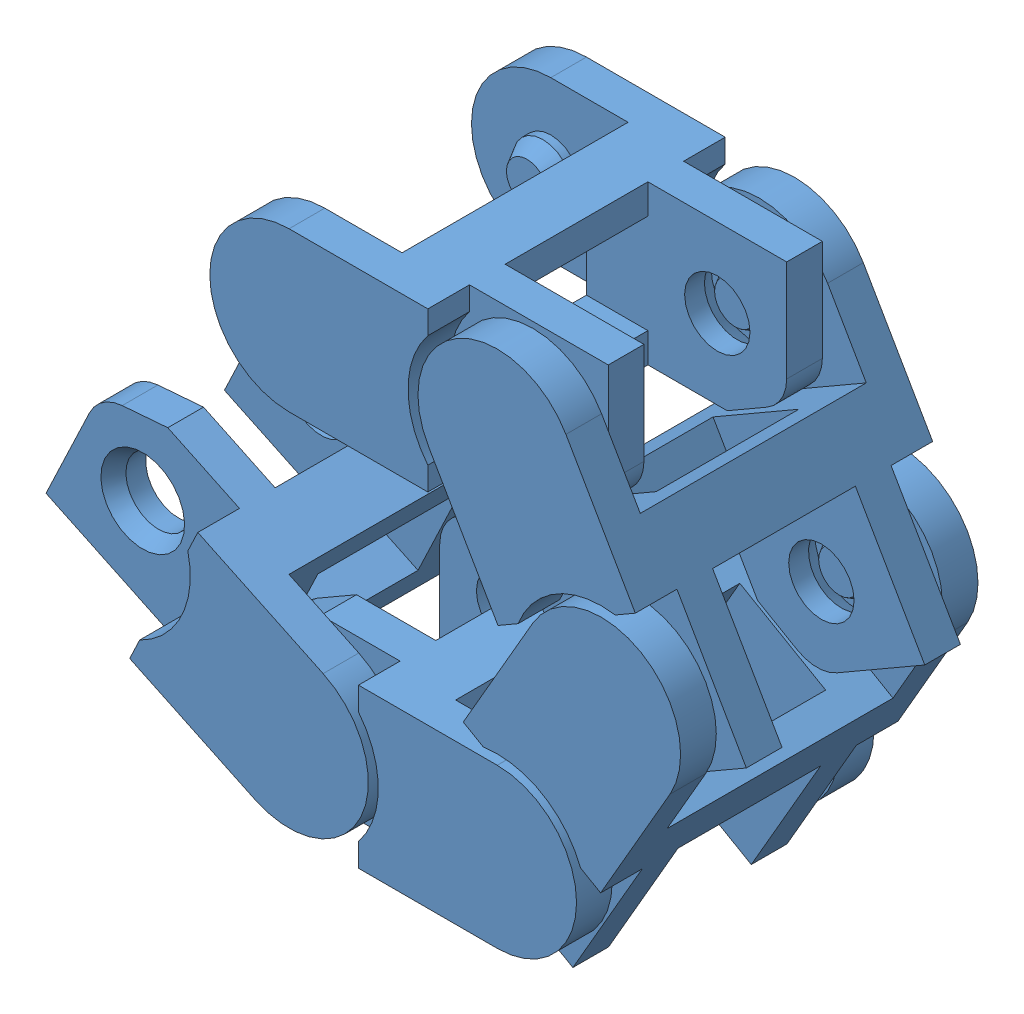
SolidWorks assembly #cable chain, configuration Valor predeterminado. Lengths in mm.
Overall size (35.58 28.98 15).
5 component instances, 1 part files, 11 mates.
Components (placement in the parent):
- cable chain-1: cable chain [Valor predeterminado] at (-3.0075 4.3458 9.5) size (18 8 15)
- cable chain-2: cable chain [Valor predeterminado] at (7.4566 -3.7164 9.5) x (0.5 -0.866025 0) z (0 0 1) size (18 8 15)
- cable chain-3: cable chain [Valor predeterminado] at (5.7066 -16.8096 9.5) x (-0.5 -0.866025 0) z (0 0 1) size (18 8 15)
- cable chain-4: cable chain [Valor predeterminado] at (-6.5075 -21.8407 9.5) x (-1 0 0) z (0 0 1) size (18 8 15)
- cable chain-5: cable chain [Valor predeterminado] at (-18.047 -18.4465 9.5) x (-0.903069 0.429496 0) z (0 0 1) size (18 8 15)
Mates (geometry in assembly coordinates):
- Concêntrico1: concentric anti-aligned: cylinder of cable chain-1 through (0.4925 0.3458 17) axis (0 0 -1) radius 1.65; cylinder of cable chain-2 through (0.4925 0.3458 14) axis (0 0 1) radius 1.5
- Largura1: width anti-aligned: plane of cable chain-2 through (-4.9716 1.8099 3.8) normal (0 0 1); plane of cable chain-2 through (-1.0216 -5.0317 15.2) normal (0 0 -1); plane of cable chain-1 through (3.9925 -3.6542 4.1) normal (0 0 -1); plane of cable chain-1 through (3.9925 -3.6542 14.9) normal (0 0 1)
- Paralelo1: parallel anti-aligned: plane of cable chain-1 through (3.9925 -1.9221 17) normal (0.5 -0.866025 0); plane of cable chain-2 through (-1.0216 -5.0317 3.8) normal (-0.5 0.866025 0)
- Largura2: width anti-aligned: plane of cable chain-4 through (4.4925 -13.8407 3.8) normal (0 0 1); plane of cable chain-4 through (-3.4075 -13.8407 15.2) normal (0 0 -1); plane of cable chain-3 through (-4.7216 -18.8718 4.1) normal (0 0 -1); plane of cable chain-3 through (-4.7216 -18.8718 14.9) normal (0 0 1)
- Concêntrico2: concentric anti-aligned: cylinder of cable chain-3 through (0.4925 -17.8407 17) axis (0 0 -1) radius 1.65; cylinder of cable chain-4 through (0.4925 -17.8407 14) axis (0 0 1) radius 1.5
- Paralelo2: parallel anti-aligned: plane of cable chain-3 through (-3.2216 -19.7378 17) normal (-1 0 0); plane of cable chain-4 through (-3.4075 -13.8407 3.8) normal (1 0 0)
- Concêntrico3: concentric aligned: cylinder of cable chain-2 through (5.7425 -8.7474 17) axis (0 0 -1) radius 1.65; cylinder of cable chain-3 through (5.7425 -8.7474 5) axis (0 0 -1) radius 1.5
- Coincidente2: coincident aligned: plane of cable chain-2 through (0.4925 0.3458 17) normal (0 0 1); plane of cable chain-3 through (5.7425 -8.7474 17) normal (0 0 1)
- Paralelo3: parallel aligned: line of cable chain-2 through (2.5284 -11.1805 4.1) axis (0.866025 -0.5 0); line of cable chain-3 through (0.3284 -10.1249 3.8) axis (0.866025 -0.5 0)
- Concêntrico5: concentric aligned: cylinder of cable chain-4 through (-10.0075 -17.8407 17) axis (0 0 -1) radius 1.65; cylinder of cable chain-5 through (-10.0075 -17.8407 5) axis (0 0 -1) radius 1.5
- Coincidente4: coincident aligned: plane of cable chain-4 through (0.4925 -17.8407 17) normal (0 0 1); plane of cable chain-5 through (-10.0075 -17.8407 17) normal (0 0 1)
